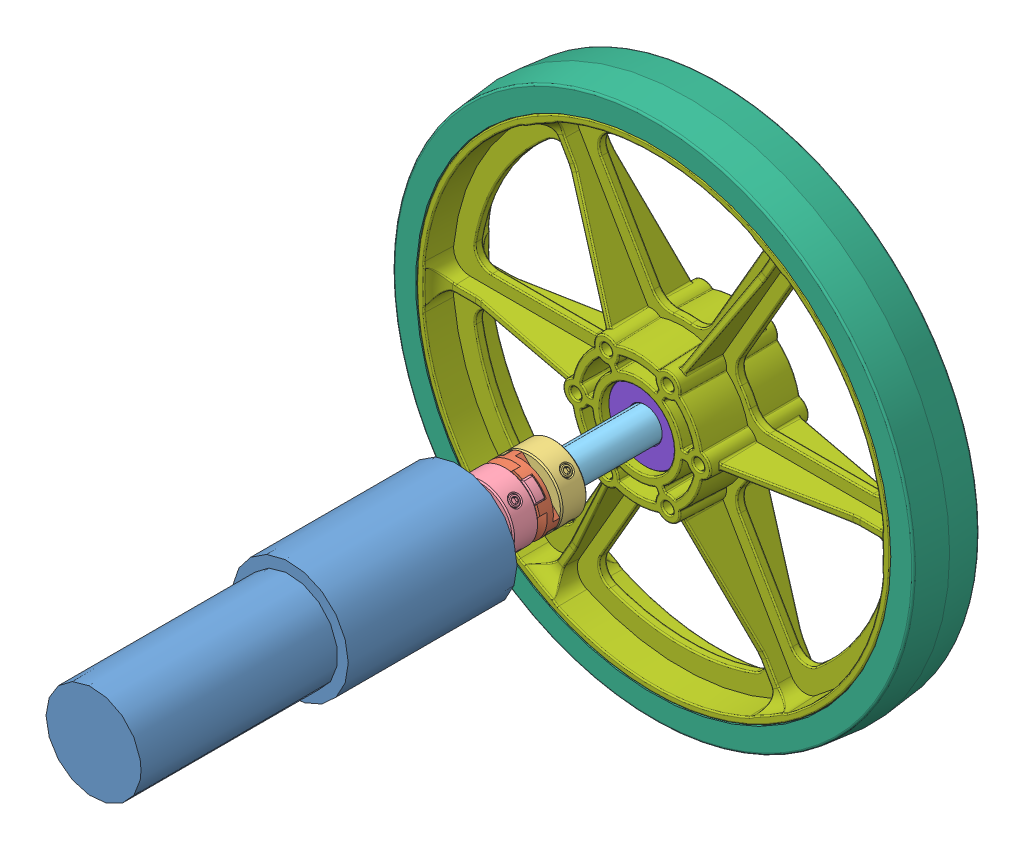
SolidWorks assembly Motor_Coupler_WheelAssy, configuration Default. Lengths in mm.
Overall size (204.35 204.35 248.71).
11 component instances, 8 part files, 6 mates.
Components (placement in the parent):
- Motor-1: Motor [Default] at (-2.7115 -11.3995 12.6743) size (45.1 45.1 159.4)
- Coupler_Assembly-1: Coupler_Assembly [Default] at (-18.5282 -16.0979 -94.9854) x (0.697262 -0.716816 0) z (0 0 1) size (25.52 25.52 28.68)
  - CouplingCenter_59985K630-1: CouplingCenter_59985K630 [59985K63] at (7.6605 14.6137 19.5344) size (25.4 25.4 7.92)
  - halfInCoupling_59985K190-1: halfInCoupling_59985K190 [59985K19] at (7.6605 14.6137 19.4804) size (25.52 25.52 14.06)
  - 10mmCoupling_59985K305-1: 10mmCoupling_59985K305 [59985K305] at (7.6605 14.6137 19.5884) x (0 1 0) z (0 0 -1) size (25.52 25.52 14.06)
- HalfInch_Shaft-1: HalfInch_Shaft [Default] at (-2.7115 -11.3995 -156.5786) size (12.7 12.7 76.2)
- 8inWheel_AndyMarkAlternative-1: 8inWheel_AndyMarkAlternative [Default] at (-2.7115 -11.3995 -153.4798) size (204.35 204.35 38.11)
  - 2010 8 tread-1: 2010 8 tread [Default] at (0 0 12.7) size (204.35 204.35 25.4)
  - 2010 8 hub-1: 2010 8 hub [Default] at origin size (190.5 190.5 38.11)
  - r8 bearing-1: r8 bearing [Default] at (0 0 -3.0988) x (-0.726935 0.686706 0) z (0 0 1) size (28.57 28.57 6.35)
  - r8 bearing-2: r8 bearing [Default] at (0 0 28.575) x (0.399336 0.916804 0) z (0 0 -1) size (28.57 28.57 6.35)
Mates (geometry in assembly coordinates):
- Concentric1: concentric anti-aligned: cylinder of Motor-1 through (-2.7115 -11.3995 -70.5234) axis (0 0 1) radius 4.9911; cylinder of Coupler_Assembly-1/10mmCoupling_59985K305-1 through (-2.7115 -11.3995 -61.1095) axis (0 0 -1) radius 5
- Coincident1: coincident aligned: plane of Motor-1 through (-2.7115 -11.3995 -70.5234) normal (0 0 -1); circle of Coupler_Assembly-1/10mmCoupling_59985K305-1
- Concentric2: concentric anti-aligned: cylinder of Coupler_Assembly-1/halfInCoupling_59985K190-1 through (-2.7115 -11.3995 -89.7924) axis (0 0 1) radius 6.35; cylinder of HalfInch_Shaft-1 through (-2.7115 -11.3995 -80.3786) axis (0 0 -1) radius 6.35
- Coincident2: coincident aligned: circle of Coupler_Assembly-1/halfInCoupling_59985K190-1; plane of HalfInch_Shaft-1 through (-2.7115 -11.3995 -80.3786) normal (0 0 1)
- Concentric3: concentric anti-aligned: cylinder of HalfInch_Shaft-1 through (-2.7115 -11.3995 -80.3786) axis (0 0 -1) radius 6.35; cylinder of 8inWheel_AndyMarkAlternative-1/r8 bearing-2 through (-2.7115 -11.3995 -131.2548) axis (0 0 1) radius 6.35
- Coincident3: coincident aligned: plane of HalfInch_Shaft-1 through (-2.7115 -11.3995 -156.5786) normal (0 0 -1); plane of 8inWheel_AndyMarkAlternative-1/r8 bearing-1 through (-2.7115 -11.3995 -156.5786) normal (0 0 -1)
